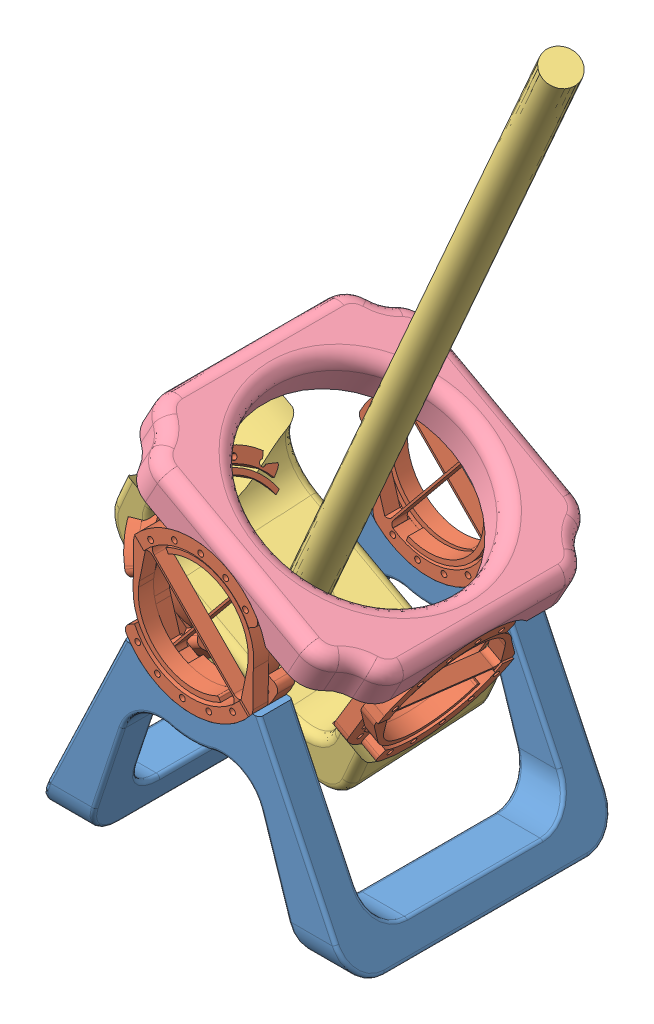
SolidWorks assembly Assemebly, configuration Default. Lengths in mm.
Overall size (202.97 287.86 97.11).
11 component instances, 4 part files, 15 mates.
Components (placement in the parent):
- Base-1: Base [Default] at origin size (93.72 57.56 80.11)
- Flexure Spring-2: Flexure Spring [Default] at (-18.5806 25.1438 37.25) x (0.135412 0.990789 0) z (0 0 -1) size (44.99 38.43 5)
- Flexure Spring-3: Flexure Spring [Default] at (-19.4998 44.1832 32.75) x (0.227533 -0.97377 0) z (0 0 1) size (44.99 38.43 5)
- Whisker base-4: Whisker base [Default] at (-65.3486 -0.6235 -41.0415) x (0.877498 -0.47958 0) z (-0.079587 -0.145622 0.986134) size (80 274 40)
- Flexure Spring-6: Flexure Spring [Default] at (23.853 1.5123 10.6767) x (0.441822 0.808412 0.388926) z (-0.877498 0.47958 0) size (44.99 38.43 5)
- Flexure Spring-7: Flexure Spring [Default] at (22.5922 8.5885 -17.0099) x (0.47958 0.877498 0) z (0.877498 -0.47958 0) size (44.99 38.43 5)
- Top-2: Top [Default] at (47.8718 39.7259 -40) x (-0.877498 0.47958 0) z (0 0 1) size (80 11.36 80)
- Flexure Spring-8: Flexure Spring [Default] at (-35.2008 22.2756 20.6659) x (0.441822 -0.808412 -0.388926) z (0.877498 0.47958 0) size (44.99 38.43 5)
- Flexure Spring-9: Flexure Spring [Default] at (-34.9097 31.1262 -17.0099) x (0.47958 -0.877498 0) z (-0.877498 -0.47958 0) size (44.99 38.43 5)
- Flexure Spring-10: Flexure Spring [Default] at (-18.5806 25.1438 -37.75) x (0.135412 0.990789 0) z (0 0 -1) size (44.99 38.43 5)
- Flexure Spring-11: Flexure Spring [Default] at (-19.4998 44.1832 -32.25) x (0.227533 -0.97377 0) z (0 0 1) size (44.99 38.43 5)
Mates (geometry in assembly coordinates):
- Coincident1: coincident aligned: plane of Base-1 through (0 0 0) normal (0 0 1)
- Coincident2: coincident aligned: plane of Base-1 through (0 0 0) normal (0 1 0)
- Coincident3: coincident aligned: plane of Base-1 through (0 0 0) normal (1 0 0)
- Concentric1: concentric anti-aligned: cylinder of Base-1 through (0 35.53 40) axis (0 0 -1) radius 22.5; cylinder of Flexure Spring-2 through (0 35.53 35) axis (0 0 1) radius 22.4585
- Coincident4: coincident aligned: plane of Base-1 through (-9.0617 -5.0062 40) normal (0 0 1); plane of Flexure Spring-2 through (-0.0005 35.698 40) normal (0 0 1)
- Concentric2: concentric aligned: cylinder of Base-1 through (0 35.53 40) axis (0 0 -1) radius 22.5; cylinder of Flexure Spring-3 through (0 35.53 35) axis (0 0 -1) radius 22.4729
- Coincident5: coincident aligned: plane of Base-1 through (-47.4424 22.03 30) normal (0 0 -1); plane of Flexure Spring-3 through (0 35.53 30) normal (0 0 -1)
- Concentric3: concentric anti-aligned: cylinder of Whisker base-4 through (35.0966 16.3488 -0.0069) axis (-0.877498 0.47958 0) radius 22.5; cylinder of Flexure Spring-6 through (30.7083 18.7472 -0.0069) axis (0.877498 -0.47958 0) radius 22.4585
- Coincident6: coincident aligned: plane of Whisker base-4 through (28.6292 4.5172 18.0052) normal (0.877498 -0.47958 0); plane of Flexure Spring-6 through (35.165 16.4758 0.0793) normal (0.877498 -0.47958 0)
- Concentric4: concentric aligned: cylinder of Whisker base-4 through (35.0966 16.3488 -0.0069) axis (-0.877498 0.47958 0) radius 22.5; cylinder of Flexure Spring-7 through (30.7083 18.7472 -0.0069) axis (-0.877498 0.47958 0) radius 22.4585
- Coincident7: coincident anti-aligned: plane of Flexure Spring-6 through (30.7775 18.8737 0.0793) normal (-0.877498 0.47958 0); plane of Flexure Spring-7 through (30.7881 18.8932 -0.0301) normal (0.877498 -0.47958 0)
- Concentric9: concentric aligned: cylinder of Flexure Spring-2 through (0.0239 35.5838 35) axis (0 0 1) radius 22.4729; cylinder of Top-2 through (0.0239 35.5838 30) axis (0 0 1) radius 22.5
- Coincident10: coincident aligned: plane of Flexure Spring-2 through (0.0239 35.5838 40) normal (0 0 1); plane of Top-2 through (28.2778 37.4945 40) normal (0 0 1)
- Concentric10: concentric aligned: cylinder of Flexure Spring-6 through (30.7363 18.7985 0) axis (0.877498 -0.47958 0) radius 22.4729; cylinder of Top-2 through (26.3488 21.1964 0) axis (0.877498 -0.47958 0) radius 22.5
- Coincident11: coincident aligned: plane of Flexure Spring-6 through (35.1238 16.4006 0) normal (0.877498 -0.47958 0); plane of Top-2 through (42.4262 29.7619 -23.8764) normal (0.877498 -0.47958 0)
